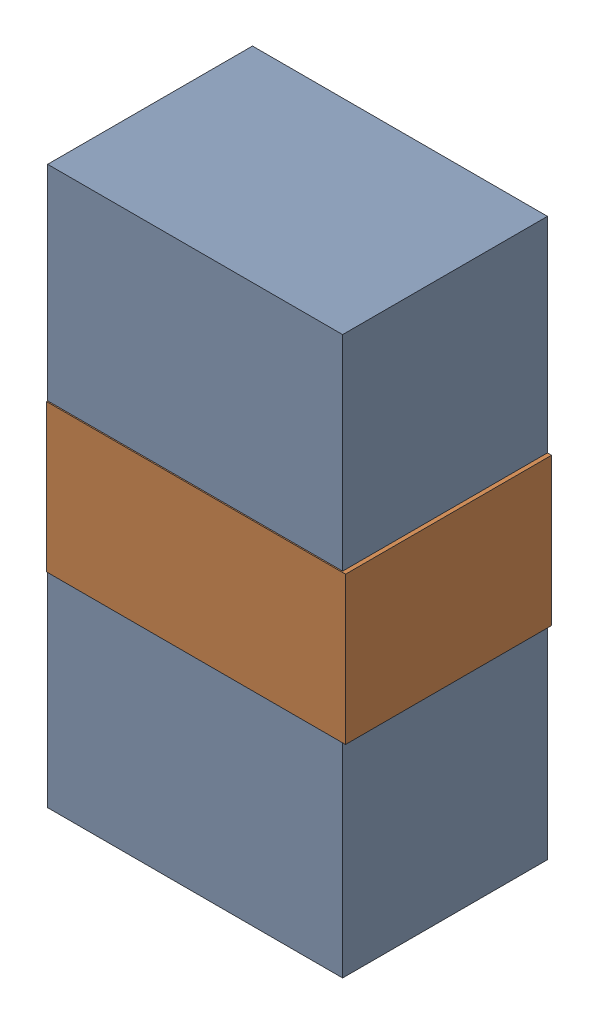
SolidWorks assembly LED2_Motor_8Kanaloa_v2.0.0_Motor, configuration Default. Lengths in mm.
Overall size (1.83 3.4 1.26).
4 component instances, 2 part files, 0 mates.
Components (placement in the parent):
- 334788016-1: 334788016 [Default] at (127.9995 145.415 0) size (1.8 3.4 1.25)
  - Extruded_12-1: Extruded_12 [Default] at origin size (1.8 3.4 1.25)
- 334787760-1: 334787760 [Default] at (128.012 145.415 0) size (1.83 0.9 1.26)
  - Extruded_13-1: Extruded_13 [Default] at origin size (1.83 0.9 1.26)
